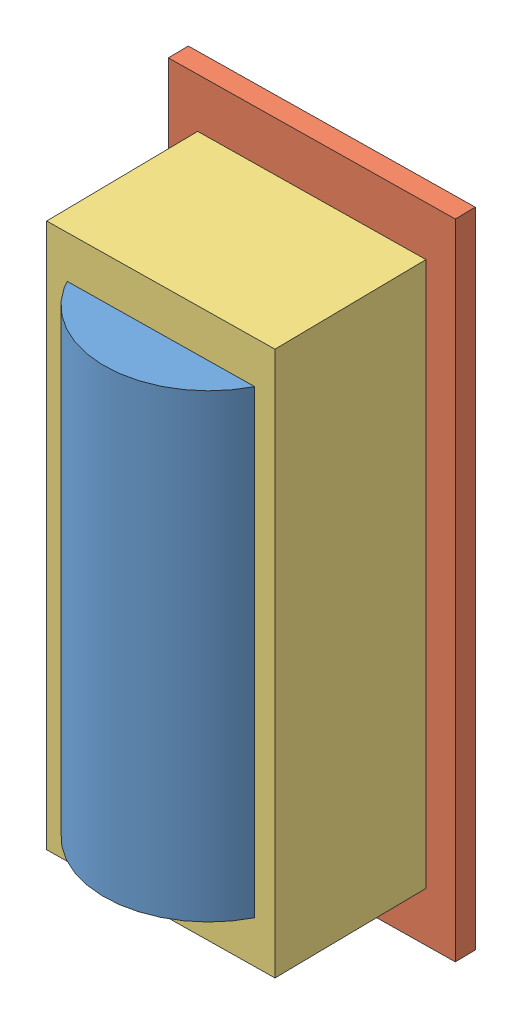
SolidWorks assembly Board ASs, configuration Default. Lengths in mm.
Overall size (22.37 50.8 18.38).
3 component instances, 3 part files, 6 mates.
Components (placement in the parent):
- 18350-1: 18350 [Default] at (1.8727 -66.1461 2.2402) x (0.999903 0 -0.013921) z (0.013921 0 0.999903) size (16.51 36.32 16.51)
- Board-1: Board [Default] at (1.7466 -66.1461 -6.814) x (0.999903 0 -0.013921) z (0 1 0) size (22.35 1.6 50.8)
- 16340 holder-1: 16340 holder [Default] at (1.7578 -66.1461 -6.014) x (0 1 0) z (0.013921 0 0.999903) size (43 17.78 12.09)
Mates (geometry in assembly coordinates):
- Tangent1: tangent anti-aligned: cylinder of 18350-1 through (1.8727 -47.9851 2.2402) axis (0 -1 0) radius 8.255; plane of Board-1 through (1.7578 -66.1461 -6.014) normal (0.013921 0 0.999903)
- Coincident19: coincident aligned: plane of 18350-1; plane of Board-1 through (1.7466 -66.1461 -6.814) normal (0 1 0)
- Coincident20: coincident aligned: plane of 18350-1 through (1.8727 -66.1461 2.2402) normal (0.999903 0 -0.013921); plane of Board-1
- Coincident21: coincident anti-aligned: plane of Board-1 through (1.7578 -66.1461 -6.014) normal (0.013921 0 0.999903); plane of 16340 holder-1 through (1.7578 -66.1461 -6.014) normal (-0.013921 0 -0.999903)
- Coincident22: coincident anti-aligned: plane of Board-1; plane of 16340 holder-1
- Coincident23: coincident aligned: plane of Board-1 through (1.7466 -66.1461 -6.814) normal (0 1 0); plane of 16340 holder-1
